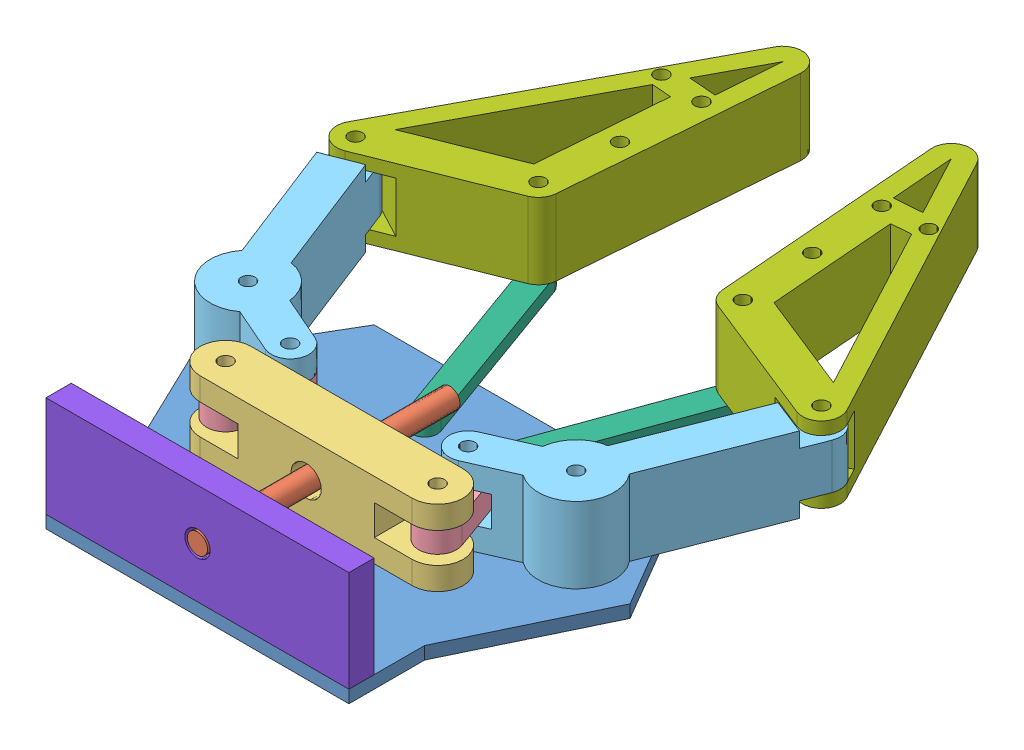
SolidWorks assembly Assem1, configuration Default. Lengths in mm.
Overall size (217.94 45 277.32).
12 component instances, 8 part files, 26 mates.
Components (placement in the parent):
- Part1-1: Part1 [Default] at (97.7191 57.4983 200.5445) size (172.77 5 130)
- Part2-1: Part2 [Default] at (97.7191 82.4983 100.5716) x (1 0 0) z (0 -1 0) size (8 100 8)
- Part3-1: Part3 [Default] at (97.7191 67.4983 147.4179) size (104.17 30 20.17)
- Part4-1: Part4 [Default] at (62.4831 78.4983 128.5964) x (-0.941074 0 -0.338202) z (0.338202 0 -0.941074) size (15 10 35)
- Part5-1: Part5 [Default] at (32.7191 67.4983 115.5445) x (0.931552 0 -0.363608) z (0.363608 0 0.931552) size (45.48 30 112.98)
- Part6-1: Part6 [Default] at (82.7191 62.4983 95.5445) x (0.940582 0 -0.339568) z (0.339568 0 0.940582) size (10 5 85)
- Part7-1: Part7 [Default] at (55.291 68.4983 49.6435) x (0.99685 0 0.079307) z (-0.079307 0 0.99685) size (65 30 129.72)
- Part8-1: Part8 [Default] at (37.7191 62.4983 200.5716) x (0 1 0) z (-1 0 0) size (40 10 120)
- Part4-2: Part4 [Default] at (139.7191 78.4983 147.4179) x (0.941074 0 -0.338202) z (0.338202 0 0.941074) size (15 10 35)
- Part5-2: Part5 [Default] at (162.7191 97.4983 115.5445) x (-0.931552 0 -0.363608) z (-0.363608 0 0.931552) size (45.48 30 112.98)
- Part7-2: Part7 [Default] at (140.1472 98.4983 49.6435) x (-0.99685 0 0.079307) z (0.079307 0 0.99685) size (65 30 129.72)
- Part6-3: Part6 [Default] at (112.7191 62.4983 95.5445) x (0.940582 0 0.339568) z (-0.339568 0 0.940582) size (10 5 85)
Mates (geometry in assembly coordinates):
- Coincident1: coincident aligned: plane of Part1-1 through (37.7191 62.4983 200.5445) normal (-1 0 0); plane of Part8-1 through (37.7191 62.4983 190.5716) normal (-1 0 0)
- Coincident2: coincident aligned: plane of Part1-1 through (97.7191 62.4983 200.5716) normal (0 0 1); plane of Part8-1 through (37.7191 62.4983 200.5716) normal (0 0 1)
- Coincident3: coincident anti-aligned: plane of Part1-1 through (97.7191 62.4983 200.5445) normal (0 1 0); plane of Part8-1 through (37.7191 62.4983 190.5716) normal (0 -1 0)
- Concentric1: concentric anti-aligned: cylinder of Part2-1 through (97.7191 82.4983 200.5716) axis (0 0 -1) radius 4; cylinder of Part8-1 through (97.7191 82.4983 190.5716) axis (0 0 1) radius 5
- Coincident4: coincident aligned: plane of Part2-1 through (97.7191 82.4983 200.5716) normal (0 0 1); plane of Part8-1 through (37.7191 62.4983 200.5716) normal (0 0 1)
- Concentric2: concentric aligned: cylinder of Part2-1 through (97.7191 82.4983 200.5716) axis (0 0 -1) radius 4; cylinder of Part3-1 through (97.7191 82.4983 164.3326) axis (0 0 -1) radius 6
- Concentric3: concentric aligned: cylinder of Part1-1 through (32.7191 62.4983 115.5445) axis (0 -1 0) radius 2.75; cylinder of Part5-1 through (32.7191 97.4983 115.5445) axis (0 -1 0) radius 2.75
- Concentric5: concentric aligned: cylinder of Part4-1 through (62.4831 88.4983 128.5964) axis (0 -1 0) radius 2.75; cylinder of Part5-1 through (62.4831 97.4983 128.5964) axis (0 -1 0) radius 2.75
- Concentric6: concentric aligned: cylinder of Part3-1 through (55.7191 97.4983 147.4179) axis (0 -1 0) radius 2.75; cylinder of Part4-1 through (55.7191 88.4983 147.4179) axis (0 -1 0) radius 2.75
- Coincident5: coincident anti-aligned: plane of Part4-1 through (62.4831 88.4983 128.5964) normal (0 1 0); plane of Part5-1 through (28.9039 88.4983 124.2448) normal (0 -1 0)
- Coincident6: coincident anti-aligned: plane of Part3-1 through (97.7191 88.4983 164.3326) normal (0 -1 0); plane of Part4-1 through (62.4831 88.4983 128.5964) normal (0 1 0)
- Concentric7: concentric anti-aligned: cylinder of Part5-1 through (5.4485 97.4983 45.6781) axis (0 -1 0) radius 2.75; circle of Part7-1
- Coincident8: coincident anti-aligned: plane of Part5-1 through (-11.5297 73.4983 132.8159) normal (0 -1 0); plane of Part7-1 through (38.2341 73.4983 40.5366) normal (0 1 0)
- Concentric8: concentric aligned: cylinder of Part6-1 through (57.2515 67.4983 25.0009) axis (0 -1 0) radius 2.75; cylinder of Part7-1 through (57.2515 98.4983 25.0009) axis (0 -1 0) radius 2.75
- Concentric9: concentric aligned: cylinder of Part1-1 through (82.7191 62.4983 95.5445) axis (0 -1 0) radius 2.75; cylinder of Part6-1 through (82.7191 67.4983 95.5445) axis (0 -1 0) radius 2.75
- Coincident10: coincident anti-aligned: plane of Part1-1 through (97.7191 62.4983 200.5445) normal (0 1 0); plane of Part6-1 through (82.7191 62.4983 95.5445) normal (0 -1 0)
- Concentric10: concentric aligned: cylinder of Part3-1 through (139.7191 97.4983 147.4179) axis (0 -1 0) radius 2.75; cylinder of Part4-2 through (139.7191 88.4983 147.4179) axis (0 -1 0) radius 2.75
- Coincident11: coincident anti-aligned: plane of Part3-1 through (97.7191 88.4983 164.3326) normal (0 -1 0); plane of Part4-2 through (139.7191 88.4983 147.4179) normal (0 1 0)
- Concentric11: concentric anti-aligned: cylinder of Part4-2 through (132.955 88.4983 128.5964) axis (0 -1 0) radius 2.75; cylinder of Part5-2 through (132.955 67.4983 128.5964) axis (0 1 0) radius 2.75
- Coincident12: coincident anti-aligned: plane of Part4-2 through (139.7191 88.4983 147.4179) normal (0 1 0); plane of Part5-2 through (166.5342 88.4983 124.2448) normal (0 -1 0)
- Coincident16: coincident anti-aligned: plane of Part5-2 through (206.9678 73.4983 132.8159) normal (0 -1 0); plane of Part7-2 through (157.204 73.4983 40.5366) normal (0 1 0)
- Concentric14: concentric aligned: cylinder of Part5-2 through (189.9897 67.4983 45.6781) axis (0 1 0) radius 2.75; cylinder of Part7-2 through (189.9897 68.4983 45.6781) axis (0 1 0) radius 2.75
- Concentric15: concentric aligned: cylinder of Part1-1 through (112.7191 62.4983 95.5445) axis (0 -1 0) radius 2.75; cylinder of Part6-3 through (112.7191 67.4983 95.5445) axis (0 -1 0) radius 2.75
- Concentric16: concentric anti-aligned: cylinder of Part7-2 through (138.1867 68.4983 25.0009) axis (0 1 0) radius 2.75; cylinder of Part6-3 through (138.1867 67.4983 25.0009) axis (0 -1 0) radius 2.75
- Coincident18: coincident anti-aligned: plane of Part1-1 through (97.7191 62.4983 200.5445) normal (0 1 0); plane of Part6-3 through (112.7191 62.4983 95.5445) normal (0 -1 0)
- Concentric17: concentric anti-aligned: cylinder of Part1-1 through (162.7191 62.4983 115.5445) axis (0 -1 0) radius 2.75; cylinder of Part5-2 through (162.7191 67.4983 115.5445) axis (0 1 0) radius 2.75
